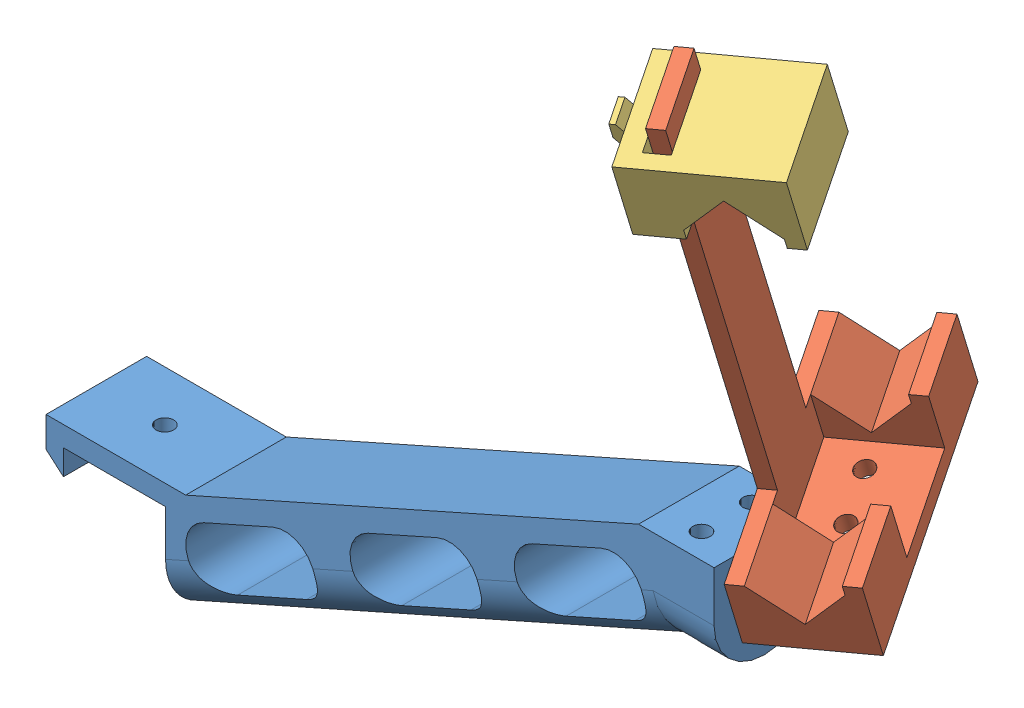
SolidWorks assembly Montagem1, configuration Valor predeterminado. Lengths in mm.
Overall size (174.42 173.32 81.77).
3 component instances, 3 part files, 3 mates.
Components (placement in the parent):
- Phone suport-1: Phone suport [Valor predeterminado] at (-74.9842 -12.9759 132.7641) size (132.76 64 20.85)
- Phone suport pt1-1: Phone suport pt1 [Valor predeterminado] at (54.4216 51.6878 114.9835) x (0.886622 0.11454 -0.448087) z (0.461102 -0.294058 0.837207) size (24 93 50)
- Phone suport pt2-1: Phone suport pt2 [Valor predeterminado] at (64.8181 127.3699 166.0593) x (0.886622 0.11454 -0.448087) z (-0.461102 0.294058 -0.837207) size (29 15 21.6)
Mates (geometry in assembly coordinates):
- Coincidente3: coincident anti-aligned: plane of Phone suport pt1-1 through (80.6028 49.6642 159.5755) normal (0.886622 0.11454 -0.448087); plane of Phone suport pt2-1 through (75.5077 125.9925 169.0048) normal (-0.886622 -0.11454 0.448087)
- Paralelo2: parallel aligned: plane of Phone suport pt1-1 through (60.2973 58.5339 135.0548) normal (-0.461102 0.294058 -0.837207); plane of Phone suport pt2-1 through (59.8382 130.5457 157.0175) normal (-0.461102 0.294058 -0.837207)
- Coincidente5: coincident anti-aligned: plane of Phone suport pt1-1 through (60.2973 58.5339 135.0548) normal (-0.461102 0.294058 -0.837207); plane of Phone suport pt2-1 through (68.3145 130.5798 155.9444) normal (0.461102 -0.294058 0.837207)
